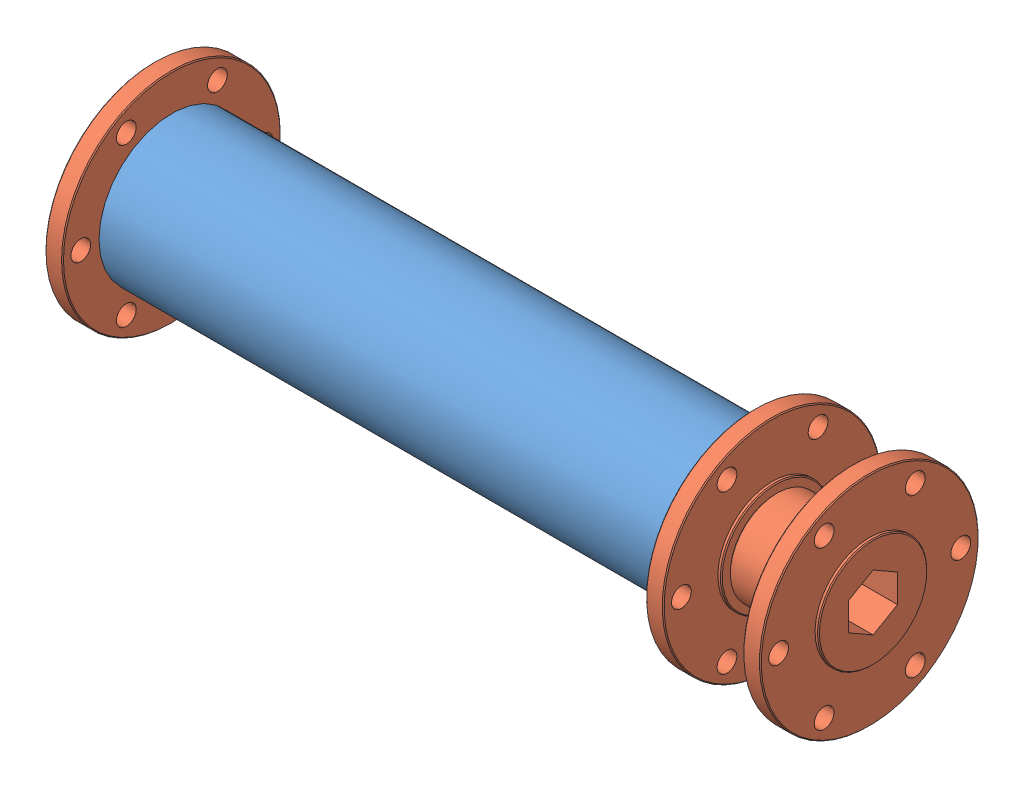
SolidWorks assembly 2018-316-A, configuration Default. Lengths in mm.
Overall size (188.72 78.07 78.07).
4 component instances, 2 part files, 8 mates.
Components (placement in the parent):
- 2018-319-D004-1: 2018-319-D004 [Default] at (-21.8207 -7.3506 16.5084) size (152.4 38.1 38.1)
- am-0096a+500+Hex+Hub+r2-1: am-0096a+500+Hex+Hub+r2 [Default] at (40.4553 -7.3506 16.5084) x (-1 0 0) z (0 -0.866025 -0.5) size (25.4 57.15 57.15)
- am-0096a+500+Hex+Hub+r2-2: am-0096a+500+Hex+Hub+r2 [Default] at (-84.0966 -7.3506 16.5084) size (25.4 57.15 57.15)
- am-0096a+500+Hex+Hub+r2-5: am-0096a+500+Hex+Hub+r2 [Default] at (65.8553 -7.3506 16.5084) x (-1 0 0) z (0 -0.866025 -0.5) size (25.4 57.15 57.15)
Mates (geometry in assembly coordinates):
- Concentric1: concentric anti-aligned: cylinder of 2018-319-D004-1 through (-167.2212 -7.3506 16.5084) axis (-1 0 0) radius 12.192; cylinder of am-0096a+500+Hex+Hub+r2-1 through (34.4403 -7.3506 16.5084) axis (1 0 0) radius 12.1666
- Coincident1: coincident anti-aligned: plane of 2018-319-D004-1 through (54.3793 11.6994 16.5084) normal (1 0 0); plane of am-0096a+500+Hex+Hub+r2-1 through (54.3793 -12.3098 13.6452) normal (-1 0 0)
- Concentric2: concentric aligned: cylinder of 2018-319-D004-1 through (-167.2212 -7.3506 16.5084) axis (-1 0 0) radius 12.192; cylinder of am-0096a+500+Hex+Hub+r2-2 through (-78.0817 -7.3506 16.5084) axis (-1 0 0) radius 12.1666
- Coincident2: coincident anti-aligned: plane of 2018-319-D004-1 through (-98.0207 11.6994 16.5084) normal (-1 0 0); plane of am-0096a+500+Hex+Hub+r2-2 through (-98.0207 -7.3506 22.2348) normal (1 0 0)
- Parallel1: parallel aligned: plane of am-0096a+500+Hex+Hub+r2-1 through (59.8403 -3.6698 22.8838) normal (0 -0.866025 -0.5); plane of am-0096a+500+Hex+Hub+r2-2 through (-103.4817 0.011 16.5084) normal (0 -0.866025 -0.5)
- Concentric3: concentric aligned: cylinder of am-0096a+500+Hex+Hub+r2-1 through (53.4903 -7.3506 16.5084) axis (1 0 0) radius 28.575; cylinder of am-0096a+500+Hex+Hub+r2-5 through (78.8903 -7.3506 16.5084) axis (1 0 0) radius 28.575
- Coincident3: coincident aligned: plane of am-0096a+500+Hex+Hub+r2-1 through (59.8403 -3.6698 22.8838) normal (0 -0.866025 -0.5); plane of am-0096a+500+Hex+Hub+r2-5 through (85.2403 -3.6698 22.8838) normal (0 -0.866025 -0.5)
- Coincident4: coincident anti-aligned: plane of am-0096a+500+Hex+Hub+r2-1 through (59.8403 -7.3506 16.5084) normal (1 0 0); plane of am-0096a+500+Hex+Hub+r2-5 through (59.8403 -7.3506 16.5084) normal (-1 0 0)
